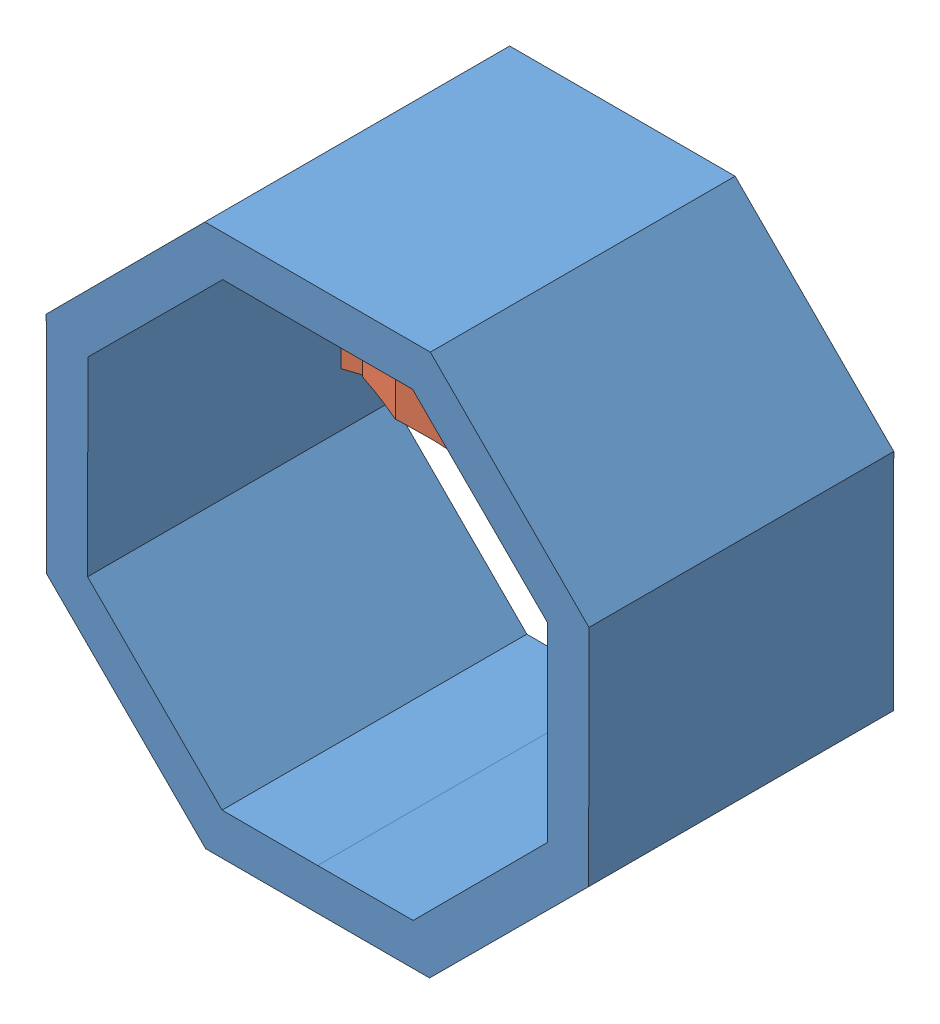
SolidWorks assembly Assem1, configuration Default. Lengths in mm.
Overall size (21.01 21 11.8).
2 component instances, 2 part files, 4 mates.
Components (placement in the parent):
- funky switch mount in bits-1: funky switch mount in bits [Default] at (6.3068 14.0395 14.8515) size (21.01 21 11.8)
- mount lock-1: mount lock [Default] at (6.2743 14.0509 3.0515) size (17.8 3.2 3.2)
Mates (geometry in assembly coordinates):
- Coincident1: coincident: plane of funky switch mount in bits-1 through (-12.2608 24.5332 16.0515) normal (0 0 -1); plane of mount lock-1 through (6.2743 14.0509 16.0515) normal (0 0 1)
- Distance1: distance = 4.255 mm: line of funky switch mount lock-1 through (1.6642 15.6509 14.0515) axis (0 0 1); line of funky switch mount in bits-1 through (-2.5878 17.7389 16.0515) axis (-0.001455 -0.999999 0)
- Parallel2: parallel: plane of funky switch mount in bits-1 through (1.9423 24.5332 16.0515) normal (0 1 0); plane of mount lock-1 through (-2.0034 15.6509 14.0515) normal (0 1 0)
- Distance2: distance = 2.085 mm: plane of mount lock-1 through (14.5424 12.4509 14.0515) normal (0 -1 0); point of funky switch mount in bits-1
